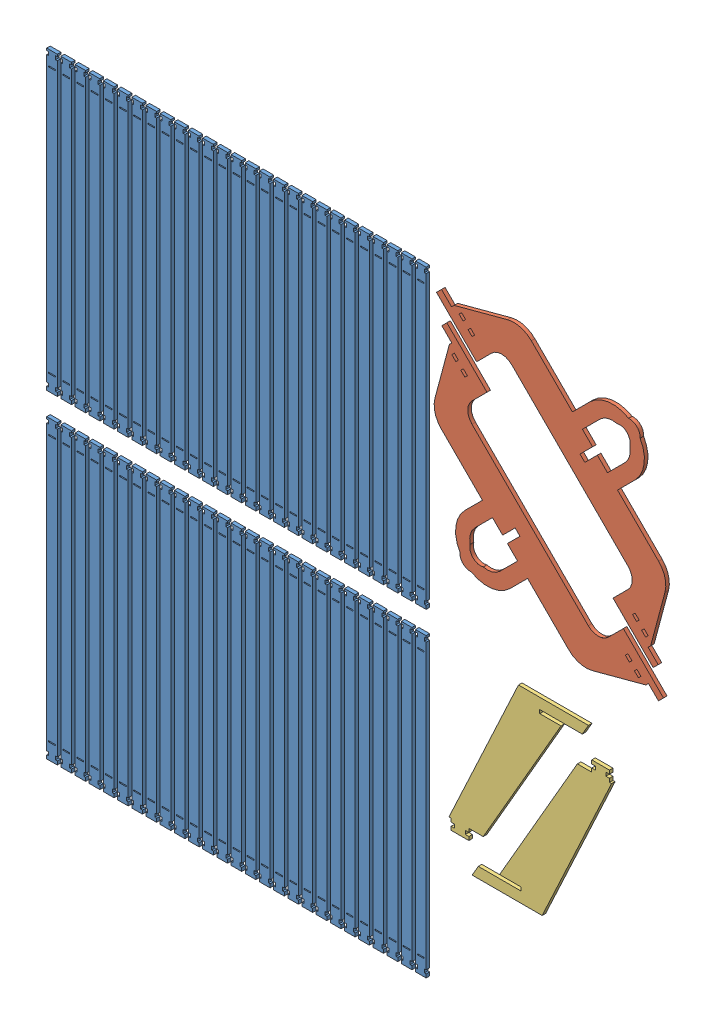
SolidWorks assembly 5mm切割排版二, configuration 默认. Lengths in mm.
Overall size (1001.84 990.23 5).
58 component instances, 3 part files, 5 mates.
Components (placement in the parent):
- 灯带背条-1: 灯带背条 [默认] at (-425.737 240.682 0) size (15 418 5)
- 灯带背条-2: 灯带背条 [默认] at (-425.737 -209.318 0) size (15 418 5)
- 灯带背条-3: 灯带背条 [默认] at (-405.737 240.682 0) size (15 418 5)
- 灯带背条-4: 灯带背条 [默认] at (-405.737 -209.318 0) size (15 418 5)
- 灯带背条-5: 灯带背条 [默认] at (-385.737 240.682 0) size (15 418 5)
- 灯带背条-6: 灯带背条 [默认] at (-385.737 -209.318 0) size (15 418 5)
- 灯带背条-7: 灯带背条 [默认] at (-365.737 240.682 0) size (15 418 5)
- 灯带背条-8: 灯带背条 [默认] at (-365.737 -209.318 0) size (15 418 5)
- 灯带背条-9: 灯带背条 [默认] at (-345.737 240.682 0) size (15 418 5)
- 灯带背条-10: 灯带背条 [默认] at (-345.737 -209.318 0) size (15 418 5)
- 灯带背条-11: 灯带背条 [默认] at (-325.737 240.682 0) size (15 418 5)
- 灯带背条-12: 灯带背条 [默认] at (-325.737 -209.318 0) size (15 418 5)
- 灯带背条-13: 灯带背条 [默认] at (-305.737 240.682 0) size (15 418 5)
- 灯带背条-14: 灯带背条 [默认] at (-305.737 -209.318 0) size (15 418 5)
- 灯带背条-15: 灯带背条 [默认] at (-285.737 240.682 0) size (15 418 5)
- 灯带背条-16: 灯带背条 [默认] at (-285.737 -209.318 0) size (15 418 5)
- 灯带背条-17: 灯带背条 [默认] at (-265.737 240.682 0) size (15 418 5)
- 灯带背条-18: 灯带背条 [默认] at (-265.737 -209.318 0) size (15 418 5)
- 灯带背条-19: 灯带背条 [默认] at (-245.737 240.682 0) size (15 418 5)
- 灯带背条-20: 灯带背条 [默认] at (-245.737 -209.318 0) size (15 418 5)
- 灯带背条-21: 灯带背条 [默认] at (-225.737 240.682 0) size (15 418 5)
- 灯带背条-22: 灯带背条 [默认] at (-225.737 -209.318 0) size (15 418 5)
- 灯带背条-23: 灯带背条 [默认] at (-205.737 240.682 0) size (15 418 5)
- 灯带背条-24: 灯带背条 [默认] at (-205.737 -209.318 0) size (15 418 5)
- 灯带背条-25: 灯带背条 [默认] at (-185.737 240.682 0) size (15 418 5)
- 灯带背条-26: 灯带背条 [默认] at (-185.737 -209.318 0) size (15 418 5)
- 灯带背条-27: 灯带背条 [默认] at (-165.737 240.682 0) size (15 418 5)
- 灯带背条-28: 灯带背条 [默认] at (-165.737 -209.318 0) size (15 418 5)
- 灯带背条-29: 灯带背条 [默认] at (-145.737 240.682 0) size (15 418 5)
- 灯带背条-30: 灯带背条 [默认] at (-145.737 -209.318 0) size (15 418 5)
- 灯带背条-31: 灯带背条 [默认] at (-125.737 240.682 0) size (15 418 5)
- 灯带背条-32: 灯带背条 [默认] at (-125.737 -209.318 0) size (15 418 5)
- 灯带背条-33: 灯带背条 [默认] at (-105.737 240.682 0) size (15 418 5)
- 灯带背条-34: 灯带背条 [默认] at (-105.737 -209.318 0) size (15 418 5)
- 灯带背条-35: 灯带背条 [默认] at (-85.737 240.682 0) size (15 418 5)
- 灯带背条-36: 灯带背条 [默认] at (-85.737 -209.318 0) size (15 418 5)
- 灯带背条-37: 灯带背条 [默认] at (-65.737 240.682 0) size (15 418 5)
- 灯带背条-38: 灯带背条 [默认] at (-65.737 -209.318 0) size (15 418 5)
- 灯带背条-39: 灯带背条 [默认] at (-45.737 240.682 0) size (15 418 5)
- 灯带背条-40: 灯带背条 [默认] at (-45.737 -209.318 0) size (15 418 5)
- 灯带背条-41: 灯带背条 [默认] at (-25.737 240.682 0) size (15 418 5)
- 灯带背条-42: 灯带背条 [默认] at (-25.737 -209.318 0) size (15 418 5)
- 灯带背条-43: 灯带背条 [默认] at (-5.737 240.682 0) size (15 418 5)
- 灯带背条-44: 灯带背条 [默认] at (-5.737 -209.318 0) size (15 418 5)
- 灯带背条-45: 灯带背条 [默认] at (14.263 240.682 0) size (15 418 5)
- 灯带背条-46: 灯带背条 [默认] at (14.263 -209.318 0) size (15 418 5)
- 灯带背条-47: 灯带背条 [默认] at (34.263 240.682 0) size (15 418 5)
- 灯带背条-48: 灯带背条 [默认] at (34.263 -209.318 0) size (15 418 5)
- 顶部挂钩横条-1: 顶部挂钩横条 [默认] at (269.1115 257.5006 0) x (0.707107 -0.707107 0) z (0 0 1) size (432 183.84 5)
- 顶部挂钩横条-2: 顶部挂钩横条 [默认] at (283.6986 227.6116 0) x (-0.707107 0.707107 0) z (0 0 1) size (432 183.84 5)
- 灯带背条-49: 灯带背条 [默认] at (54.263 240.682 0) size (15 418 5)
- 灯带背条-50: 灯带背条 [默认] at (54.263 -209.318 0) size (15 418 5)
- 灯带背条-51: 灯带背条 [默认] at (74.263 240.682 0) size (15 418 5)
- 灯带背条-52: 灯带背条 [默认] at (74.263 -209.318 0) size (15 418 5)
- 灯带背条-53: 灯带背条 [默认] at (94.263 240.682 0) size (15 418 5)
- 灯带背条-54: 灯带背条 [默认] at (94.263 -209.318 0) size (15 418 5)
- 底部退-1: 底部退 [默认] at (265.3092 -276.2262 0) size (196.58 225 5)
- 底部退-2: 底部退 [默认] at (231.952 -11.4133 0) x (-1 0 0) z (0 0 1) size (196.58 225 5)
Mates (geometry in assembly coordinates):
- 重合2: coincident anti-aligned: plane of 灯带背条-1 through (-425.737 240.682 0) normal (0 0 -1)
- 重合3: coincident anti-aligned: plane of 顶部挂钩横条-2 through (283.6986 227.6116 0) normal (0 0 -1)
- 重合4: coincident anti-aligned: plane of 顶部挂钩横条-1 through (269.1115 257.5006 0) normal (0 0 -1)
- 重合5: coincident anti-aligned: plane of 底部退-2 through (231.952 -11.4133 0) normal (0 0 -1)
- 重合6: coincident anti-aligned: plane of 底部退-1 through (265.3092 -276.2262 0) normal (0 0 -1)
